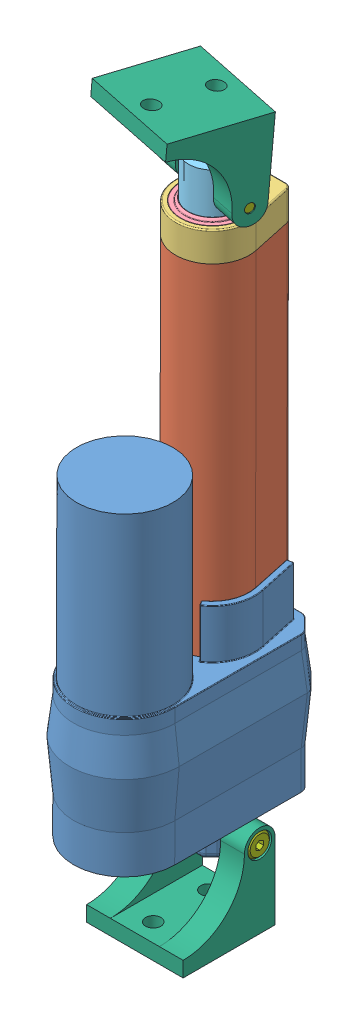
SolidWorks assembly _test - w-celvis, configuration Default. Lengths in mm.
Overall size (48.91 296.31 85.19).
12 component instances, 7 part files, 4 mates.
Components (placement in the parent):
- HDA-8-2-1: HDA-8-2 [Default] at (20.0025 43.18 -31.7715) x (1 0 0) z (0 0.001881 0.999998) size (45.73 247.71 84.91) (flexible)
  - HDA-BASE-1: HDA-BASE [Default] at origin size (45.73 149.35 84.91)
  - HDA-SHROUD-1: HDA-SHROUD [8IN] at (0 56.642 0) size (30.48 141.15 36.83)
  - HDA-SHROUD-CAP-2: HDA-SHROUD-CAP [Default] at (0 197.7965 0) size (30.48 12.19 36.83)
  - HDA-CAP-SEAL-1: HDA-CAP-SEAL [Default] at (0 207.4485 0) size (26.42 3.52 26.42)
  - HDA-STROKE-1: HDA-STROKE [8IN] at (0 227.7685 0) x (0.203405 0 -0.979095) z (-0.979095 0 -0.203405) size (19.94 220.98 20.14)
- Celvis w-bolt-1: Celvis w-bolt [Default] at origin size (40.02 38.14 38.14)
  - HDA Clevis Mount-1: HDA Clevis Mount [Default] at origin size (40 38.1 38.1)
  - socket head shoulder screw2_ai-1: socket head shoulder screw2_ai [SHSSCREW 0.25x1-N] at (40.0177 31.75 -31.75) x (-1 0 0) z (0 0.894783 -0.446501) size (39.7 9.53 9.53)
- Celvis w-bolt-2: Celvis w-bolt [Default] at (33.6665 296.3094 0.3187) x (-0.979095 -0.000383 -0.203405) z (-0.202752 0.081899 0.975799) size (40.02 38.14 38.14)
  - HDA Clevis Mount-1: HDA Clevis Mount [Default] at origin size (40 38.1 38.1)
  - socket head shoulder screw2_ai-1: socket head shoulder screw2_ai [SHSSCREW 0.25x1-N] at (40.0177 31.75 -31.75) x (-1 0 0) z (0 0.894783 -0.446501) size (39.7 9.53 9.53)
Mates (geometry in assembly coordinates):
- Concentric4: concentric aligned: cylinder of HDA-8-2-1/HDA-BASE-1 through (-2.944 31.75 -31.75) axis (1 0 0) radius 3.175; cylinder of Celvis w-bolt-1/socket head shoulder screw2_ai-1 through (46.3677 31.75 -31.75) axis (1 0 0) radius 3.1496
- Concentric5: concentric aligned: cylinder of HDA-8-2-1/HDA-STROKE-1 through (29.7636 262.062 -30.1553) axis (-0.979095 -0.000383 -0.203405) radius 3.175; cylinder of Celvis w-bolt-2/socket head shoulder screw2_ai-1 through (-5.8115 262.0481 -37.5459) axis (-0.979095 -0.000383 -0.203405) radius 3.1496
- Width1: width: plane of Celvis w-bolt-2/HDA Clevis Mount-1 through (4.0312 289.9692 -5.3068) normal (0.979095 0.000383 0.203405); plane of Celvis w-bolt-2/HDA Clevis Mount-1 through (23.9264 289.977 -1.1736) normal (-0.979095 -0.000383 -0.203405); cylinder of HDA-8-2-1/HDA-STROKE-1 through (20.0025 253.1682 -32.1664) axis (0 0.999998 -0.001881) radius 9.9695
- Width2: width anti-aligned: plane of Celvis w-bolt-1/HDA Clevis Mount-1 through (30.1625 6.35 0) normal (-1 0 0); plane of Celvis w-bolt-1/HDA Clevis Mount-1 through (9.8425 6.35 0) normal (1 0 0); plane of HDA-8-2-1/HDA-BASE-1 through (28.8925 23.2506 -26.654) normal (1 0 0); plane of HDA-8-2-1/HDA-BASE-1 through (11.1125 23.2506 -26.654) normal (-1 0 0)
